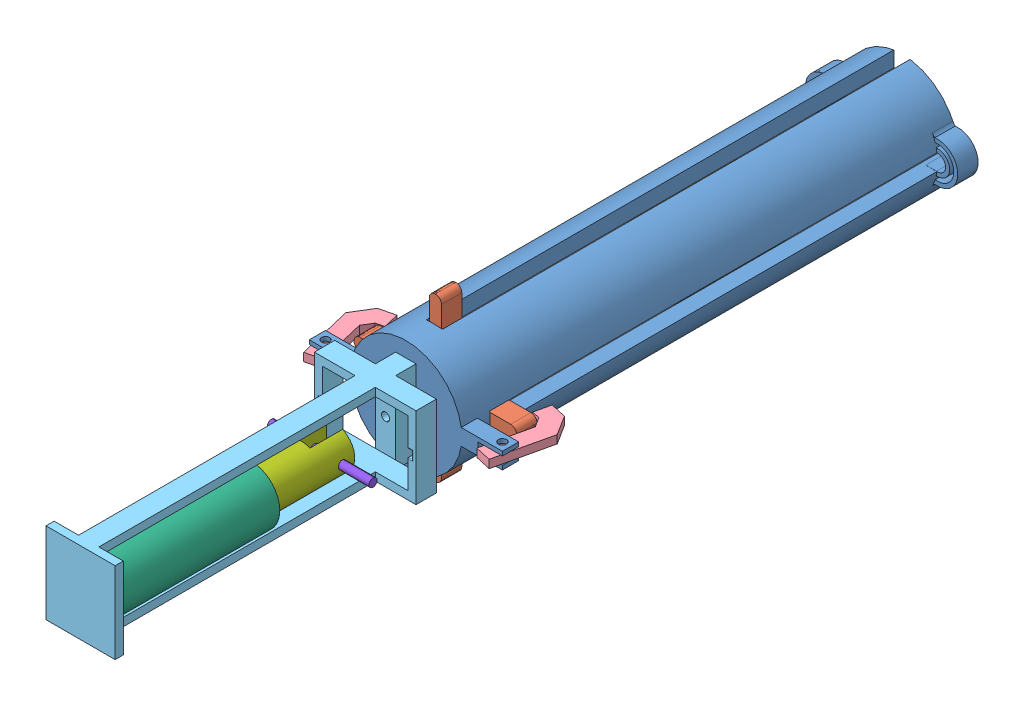
SolidWorks assembly New Shooter, configuration Default. Lengths in mm.
Overall size (68.3 50.8 256.54).
9 component instances, 8 part files, 16 mates.
Components (placement in the parent):
- SlidePath-1: SlidePath [Default] at origin size (60.32 34.92 154.94)
- Slide Cross-1: Slide Cross [Default] at (0 0 139.371) size (50.8 50.8 6.35)
- Toypedo-1: Toypedo [Default] at (0 0 10.5247) x (0 0 -1) z (1 0 0) size (123.83 34.75 34.75)
- Trigger hinge-1: Trigger hinge [Default] at (32.9203 1.27 140.5816) x (-0.222144 0 0.975014) z (0 -1 0) size (22.86 10.16 2.54)
- Trigger hinge-2: Trigger hinge [Default] at (-33.0662 -1.27 140.6481) x (0.234198 0 0.972189) z (0 1 0) size (22.86 10.16 2.54)
- Solonoid mount-1: Solonoid mount [Default] at (0 0 154.94) x (0 0 1) z (1 0 0) size (101.6 25.4 31.75)
- solonoid model-1: solonoid model [Default] at (0 0 254) x (0.923728 0.383049 0) z (0 0 -1) size (17.78 17.78 50.8)
- Solonoid plunger-1: Solonoid plunger [Default] at (0 0 177.2502) size (12.7 12.7 50.8)
- string holder-1: string holder [Default] at (0 0 181.0602) x (0 -0.343823 -0.939034) z (-1 0 0) size (2.54 2.54 31.75)
Mates (geometry in assembly coordinates):
- Parallel1: parallel anti-aligned: plane of SlidePath-1 through (-2.54 31.75 -19.05) normal (1 0 0); plane of Slide Cross-1 through (-1.905 1.905 145.721) normal (-1 0 0)
- Parallel2: parallel: plane of SlidePath-1 through (-31.75 -2.54 -19.05) normal (0 1 0); plane of Toypedo-1 through (-14.3175 0.7937 131.1747) normal (0 1 0)
- Concentric1: concentric aligned: cylinder of SlidePath-1 through (27.6225 17.4625 152.4) axis (0 -1 0) radius 1.27; cylinder of Trigger hinge-1 through (27.6225 1.271 152.4) axis (0 -1 0) radius 1.27
- Coincident1: coincident anti-aligned: plane of SlidePath-1 through (22.5425 1.27 -0.001) normal (0 -1 0); plane of Trigger hinge-1 through (34.0488 1.27 135.6285) normal (0 1 0)
- Concentric2: concentric aligned: circle of SlidePath-1; circle of Slide Cross-1
- Concentric3: concentric anti-aligned: cylinder of SlidePath-1 through (-27.6225 17.4625 152.4) axis (0 -1 0) radius 1.27; cylinder of Trigger hinge-2 through (-27.6225 -1.271 152.4) axis (0 1 0) radius 1.27
- Coincident3: coincident anti-aligned: plane of SlidePath-1 through (-22.5425 1.27 -0.001) normal (0 -1 0); plane of Trigger hinge-2 through (-34.2559 1.27 135.7093) normal (0 1 0)
- Coincident4: coincident anti-aligned: plane of SlidePath-1 through (0 0 154.94) normal (0 0 1); plane of Solonoid mount-1 through (3.175 -12.7 154.94) normal (0 0 -1)
- Concentric4: concentric anti-aligned: circle of SlidePath-1; circle of Solonoid mount-1
- Parallel4: parallel anti-aligned: line of SlidePath-1 through (30.1625 2.54 154.94) axis (0 -1 0); line of Solonoid mount-1 through (15.875 -12.7 167.64) axis (0 1 0)
- Concentric5: concentric anti-aligned: cylinder of Solonoid mount-1 through (0 0 256.541) axis (0 0 -1) radius 1.27; cylinder of solonoid model-1 through (0 0 203.2) axis (0 0 1) radius 8.89
- Coincident7: coincident anti-aligned: plane of Solonoid mount-1 through (-3.175 12.7 254) normal (0 0 -1); plane of solonoid model-1 through (0 0 254) normal (0 0 1)
- Concentric6: concentric anti-aligned: cylinder of solonoid model-1 through (0 0 203.2) axis (0 0 1) radius 6.35; cylinder of Solonoid plunger-1 through (0 0 221.7002) axis (0 0 -1) radius 6.35
- Concentric7: concentric anti-aligned: cylinder of Solonoid plunger-1 through (6.35 0 181.0602) axis (-1 0 0) radius 1.27; cylinder of string holder-1 through (-15.875 0 181.0602) axis (1 0 0) radius 1.27
- Coincident11: coincident aligned: plane of Solonoid mount-1 through (15.875 -12.7 161.29) normal (1 0 0); plane of string holder-1 through (15.875 0 181.0602) normal (1 0 0)
- Concentric9: concentric aligned: circle of SlidePath-1; circle of Toypedo-1
